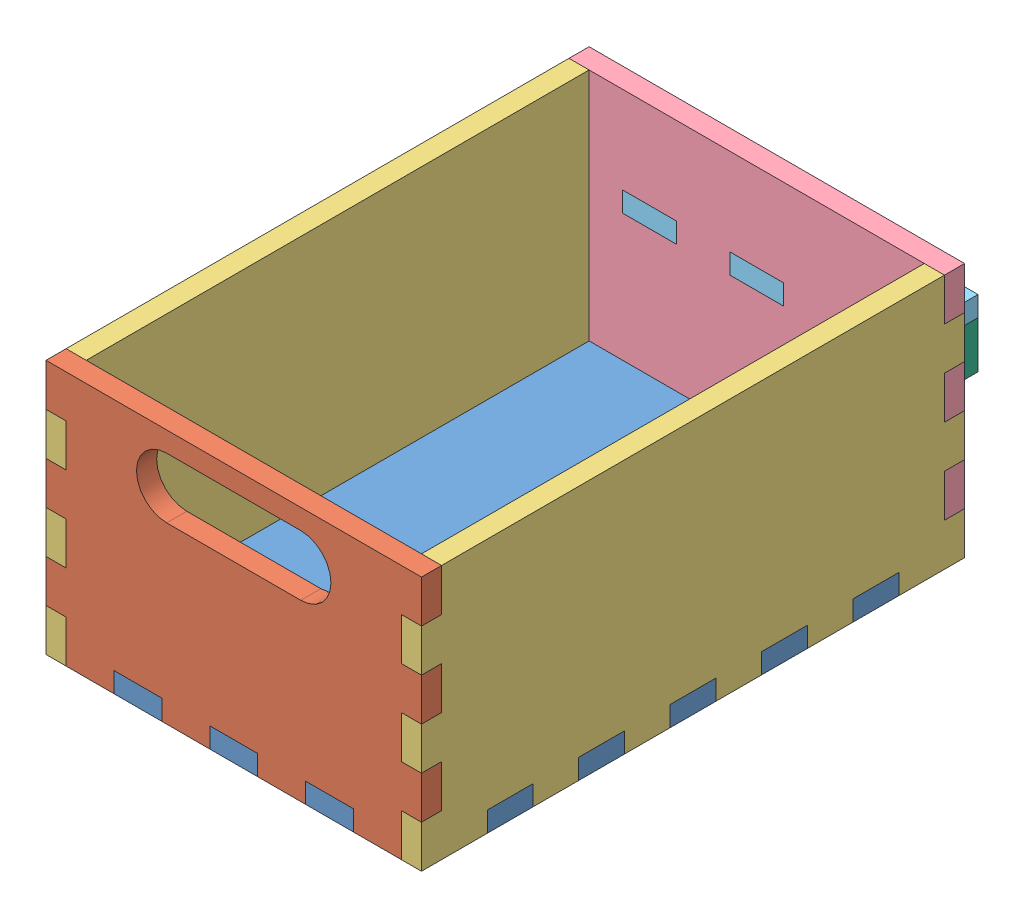
SolidWorks assembly Cassetto, configuration Default. Lengths in mm.
Overall size (56 38 91).
7 component instances, 6 part files, 5 mates.
Components (placement in the parent):
- Botton-1: Botton [Default] at (58.2113 53.9897 -20.0276) size (56 3 81)
- Front-1: Front [Default] at (58.2113 72.9897 18.9724) size (56 38 3)
- Right-1: Right [Default] at (31.7113 72.9897 -20.0276) size (3 38 81)
- Right-3: Right [Default] at (84.7113 72.9897 -20.0276) size (3 38 81)
- Back-2: Back [Default] at (58.2113 72.9897 -59.0276) size (56 38 3)
- Grip_base-2: Grip_base [Default] at (58.2113 75.9897 -64.0276) size (40 3 13)
- Grip-2: Grip [Default] at (58.2113 72.4897 -69.0276) size (40 10 3)
Mates (geometry in assembly coordinates):
- Coincidente1: coincident: point of Botton-1; point of Right-1
- Coincidente2: coincident: point of Botton-1; point of Front-1
- Coincidente8: coincident: point of Right-3; point of Back-2
- Coincidente10: coincident: point of Grip_base-2; point of Grip-2
- Coincidente11: coincident: point of Back-2; point of Grip_base-2
